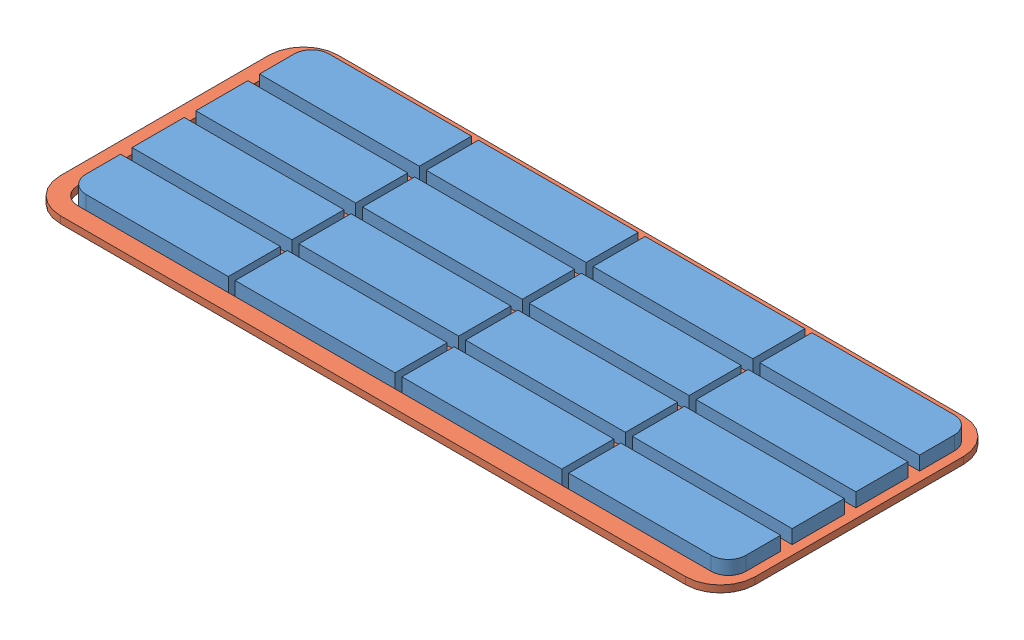
SolidWorks assembly KeypadBagianAkhir_18, configuration Default. Lengths in mm.
Overall size (100 3 40).
2 component instances, 2 part files, 0 mates.
Components (placement in the parent):
- KeypadBagian1_18-1: KeypadBagian1_18 [Default] at (40.5013 55.7056 69.4343) size (95 3 35)
- KeypadBagian2_18-1: KeypadBagian2_18 [Default] at (53.1911 55.7056 77.0769) size (100 1 40)
